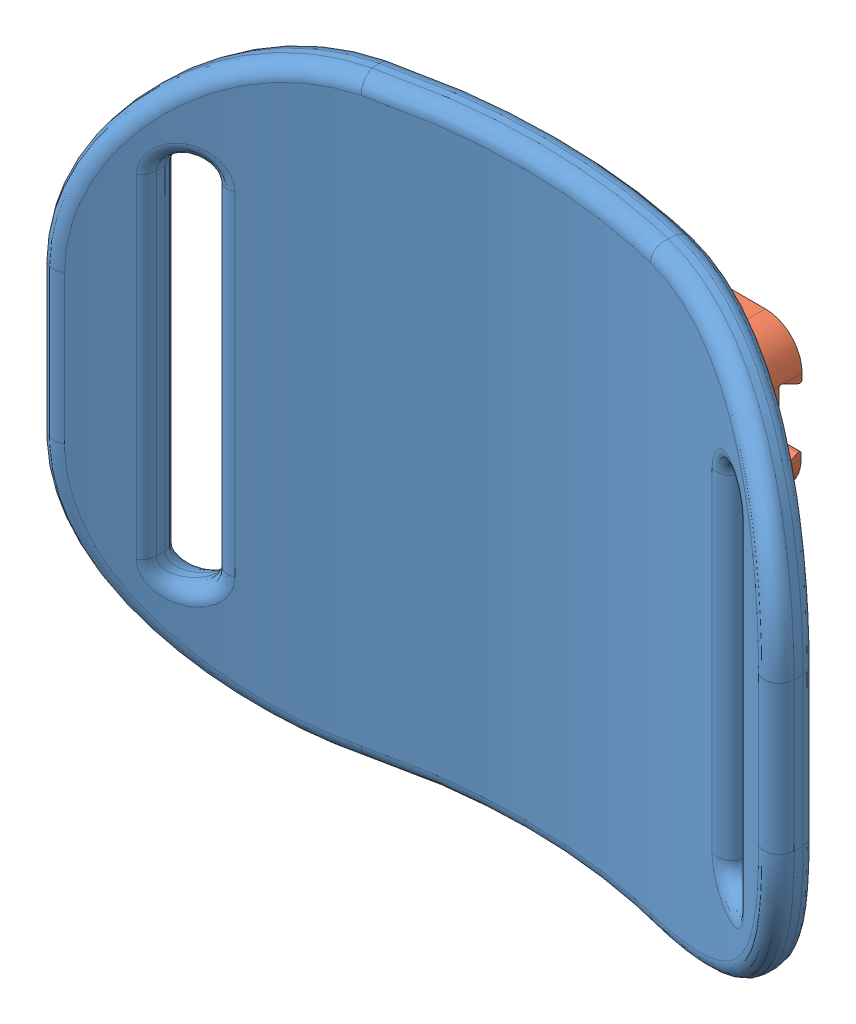
SolidWorks assembly NewThighAttachmentV3, configuration Default. Lengths in mm.
Overall size (102.14 80 45.11).
2 component instances, 2 part files, 2 mates.
Components (placement in the parent):
- slide1WideV3-1: slide1WideV3 [Default] at (-6.6431 -35.6303 80.0392) size (102.14 80 33)
- TopRailPieceV2-1: TopRailPieceV2 [Default] at (-6.6431 4.3109 -15.9605) x (1 0 0) z (0 0.999931 -0.011757) size (19 22 20)
Mates (geometry in assembly coordinates):
- Width1: width anti-aligned: plane of TopRailPieceV2-1 through (2.8569 -5.8295 -27.8421) normal (1 0 0); plane of slide1WideV3-1 through (-16.1431 -5.8295 -27.8421) normal (-1 0 0); plane of TopRailPieceV2-1 through (3.3569 -0.6303 -15.9608) normal (-1 0 0); plane of slide1WideV3-1 through (-16.6431 -0.6303 -15.9608) normal (1 0 0)
- Concentric1: concentric aligned: cylinder of slide1WideV3-1 through (-32.4413 4.3697 -10.9608) axis (1 0 0) radius 2.05; cylinder of TopRailPieceV2-1 through (-16.1431 4.3697 -10.9608) axis (1 0 0) radius 2.15
